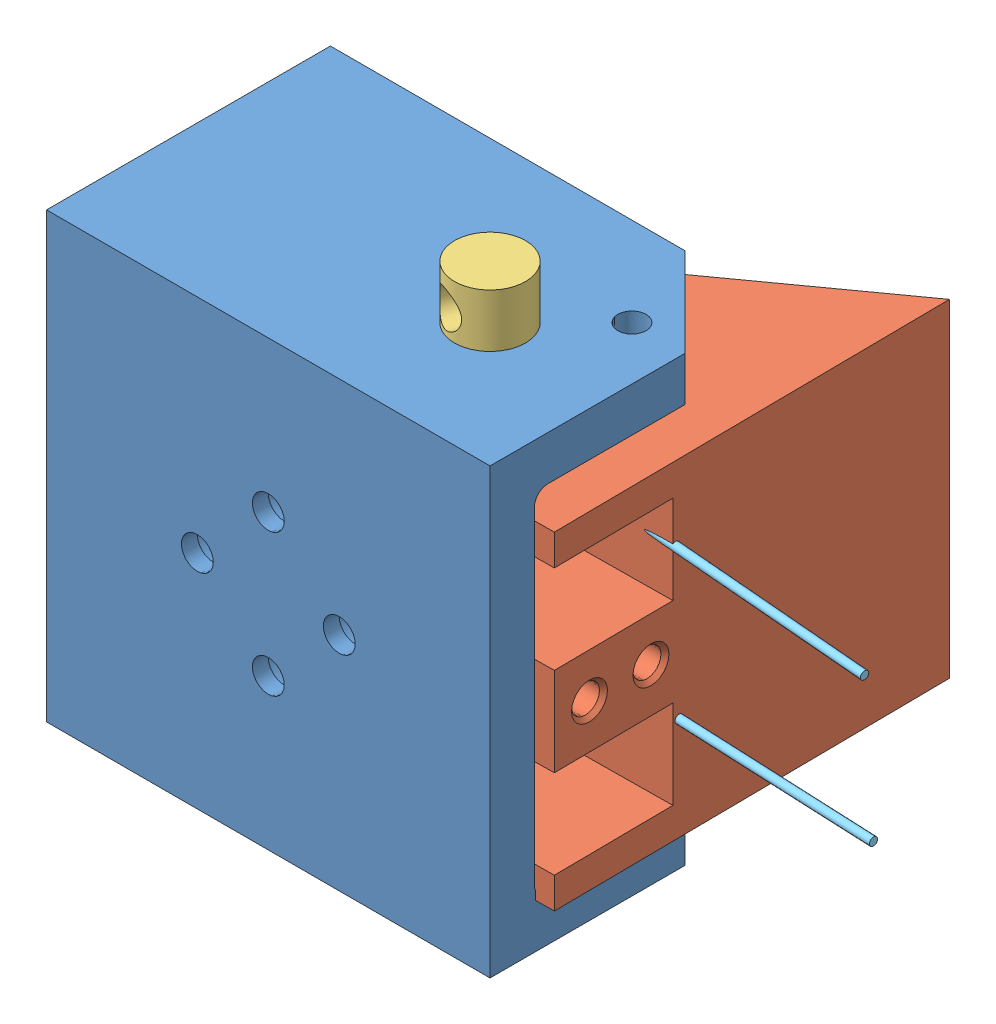
SolidWorks assembly Assembly1, configuration Default. Lengths in mm.
Overall size (38.55 31 25.08).
9 component instances, 8 part files, 9 mates.
Components (placement in the parent):
- Base better redesign-1: Base better redesign [Default] at origin size (25 25 16)
- Swing piece better redesign-1: Swing piece better redesign [Default] at (7.1852 -10 -13.5209) x (0.999949 0 -0.010122) z (0 1 0) size (13.5 22.5 18.5)
- Pin better redesign-1: Pin better redesign [Default] at (24.0606 28.965 -1.4942) x (-0.908109 0 -0.418733) z (0 -1 0) size (5 5 8.89) (hidden)
- Hinge-1: Hinge [Default] at (18.0577 93.6952 9.2292) x (-0.896344 0 -0.44336) z (0.44336 0 -0.896344) size (5.5 50 5.5) (hidden)
- Solar Panel-1: Solar Panel [Default] at (91.0794 0 -15.9235) x (0.999979 0 -0.006404) z (0 1 0) size (275 4 85) (hidden)
- Hinge mcmaster 4mm-1: Hinge mcmaster 4mm [93217A290] at (5.5 109.5 -4.5) x (-0.942504 0 -0.334195) z (0 1 0) size (8 8 31)
- Pin mcmaster_v2-1: Pin mcmaster_v2 [98378A149] at (9.4593 -39 -8.5403) x (0.996515 0 -0.083417) z (0 -1 0) size (3 3 7)
- 9271K88_Torsion Spring-1: 9271K88_Torsion Spring [9271K88] at (5.4834 4.9925 -4.7976) x (0.082262 0.990864 -0.106873) z (0.996005 -0.077998 0.043485) size (4.03 5.49 38.1)
- 9271K88_Torsion Spring-2: 9271K88_Torsion Spring [9271K88] at (5.5843 -3.9353 -4.8337) x (0.055195 0.998059 -0.028849) z (0.998261 -0.054562 0.022303) size (4.03 5.49 38.1)
Mates (geometry in assembly coordinates):
- Coincident3: coincident anti-aligned: plane of Base better redesign-1 through (-12.5 -10 -13.5) normal (0 1 0); plane of Swing piece better redesign-1 through (7.1852 -10 -13.5209) normal (0 -1 0)
- Concentric5: concentric anti-aligned: cylinder of Swing piece better redesign-1 through (5.5 8.5 -4.5) axis (0 -1 0) radius 2; cylinder of Hinge mcmaster 4mm-1 through (5.5 234.5 -4.5) axis (0 1 0) radius 2
- Coincident5: coincident anti-aligned: plane of Base better redesign-1 through (-12.5 -12.5 2.5) normal (0 -1 0); plane of Hinge mcmaster 4mm-1 through (4.1632 -12.5 -0.73) normal (0 1 0)
- Coincident6: coincident anti-aligned: plane of Base better redesign-1 through (-12.5 -12.5 2.5) normal (0 -1 0); plane of Hinge mcmaster 4mm-1 through (4.1632 -12.5 -0.73) normal (0 1 0)
- Concentric6: concentric anti-aligned: cylinder of Base better redesign-1 through (5.5 12.5 -4.5) axis (0 -1 0) radius 2; cylinder of Hinge mcmaster 4mm-1 through (5.5 234.5 -4.5) axis (0 1 0) radius 2
- Concentric7: concentric anti-aligned: cylinder of Swing piece better redesign-1 through (9.4593 1 -8.5403) axis (0 -1 0) radius 1.5; cylinder of Pin mcmaster_v2-1 through (9.4593 -5 -8.5403) axis (0 1 0) radius 1.5
- Coincident7: coincident anti-aligned: plane of Base better redesign-1 through (-12.5 -10 -13.5) normal (0 1 0); plane of Pin mcmaster_v2-1 through (9.5427 -10 -7.5438) normal (0 -1 0)
- Tangent4: tangent anti-aligned: cylinder of Hinge mcmaster 4mm-1 through (5.5 234.5 -4.5) axis (0 1 0) radius 2; face of 9271K88_Torsion Spring-1
- Tangent8: tangent anti-aligned: cylinder of Hinge mcmaster 4mm-1 through (5.5 234.5 -4.5) axis (0 1 0) radius 2; edge_curve of 9271K88_Torsion Spring-2
